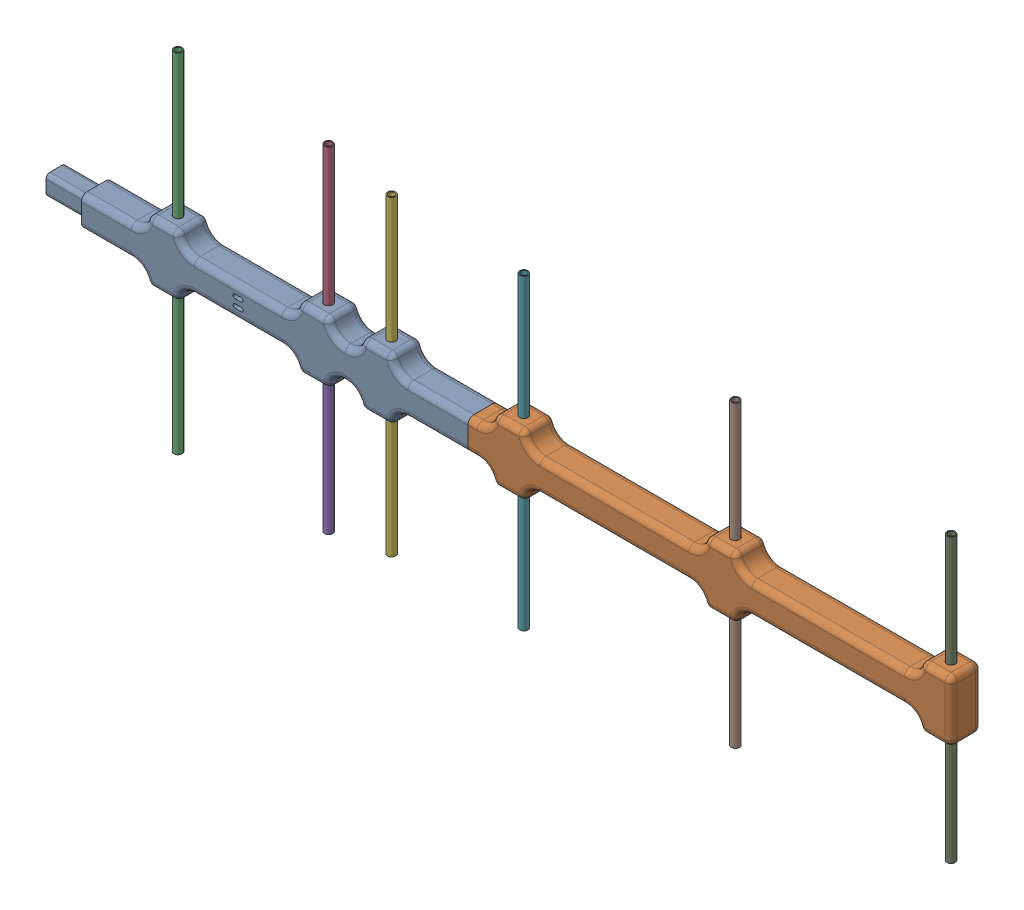
SolidWorks assembly LoRa 6 Elements 868 MHz Yagi Antenna, configuration Default. Lengths in mm.
Overall size (447.5 171 15).
9 component instances, 8 part files, 17 mates.
Components (placement in the parent):
- LoRa 6 Elements 868 MHz Yagi Antenna Back Side-1: LoRa 6 Elements 868 MHz Yagi Antenna Back Side [Default] at origin size (210 30 15)
- LoRa 6 Elements 868 MHz Yagi Antenna Front Side-1: LoRa 6 Elements 868 MHz Yagi Antenna Front Side [Default] at origin size (265.5 30 15)
- Reflector 171 mm-1: Reflector 171 mm [Default] at (-190 0 0) size (4 171 4)
- Driven Element 80mm-1: Driven Element 80mm [Default] at (-116 42.5 0) x (0.215404 0 0.976525) z (-0.976525 0 0.215404) size (4 80 4)
- Driven Element 80mm-2: Driven Element 80mm [Default] at (-116 -42.5 0) x (0.995024 0 -0.099633) z (0.099633 0 0.995024) size (4 80 4)
- Element 153mm-1: Element 153mm [Default] at (-85 0 0) x (0.953503 0 -0.301384) z (0.301384 0 0.953503) size (4 153 4)
- Element 151mm-1: Element 151mm [Default] at (-20 0 0) x (0.200414 0 -0.979711) z (0.979711 0 0.200414) size (4 151 4)
- Element 147mm-1: Element 147mm [Default] at (84 0 0) x (0.686761 0 -0.726884) z (0.726884 0 0.686761) size (4 147 4)
- Element 139mm-1: Element 139mm [Default] at (190 0 0) size (4 139 4)
Mates (geometry in assembly coordinates):
- Coincident4: coincident aligned: plane of LoRa 6 Elements 868 MHz Yagi Antenna Back Side-1 through (-200 7.5 -7.5) normal (0 0 -1); plane of DE1CTL 868 MHz Yagi Antenna Front Side-1 through (-200 7.5 -7.5) normal (0 0 -1)
- Coincident5: coincident aligned: plane of LoRa 6 Elements 868 MHz Yagi Antenna Back Side-1 through (0 -7.5 0) normal (0 -1 0); plane of DE1CTL 868 MHz Yagi Antenna Front Side-1 through (0 -7.5 0) normal (0 -1 0)
- Concentric1: concentric aligned: cylinder of LoRa 6 Elements 868 MHz Yagi Antenna Back Side-1 through (-190 -7.5 0) axis (0 -1 0) radius 2.05; cylinder of Reflector 171 mm-1 through (-190 85.5 0) axis (0 -1 0) radius 2
- Width1: width aligned: plane of Reflector 171 mm-1 through (-190 85.5 0) normal (0 1 0); plane of Reflector 171 mm-1 through (-190 -85.5 0) normal (0 -1 0); plane of LoRa 6 Elements 868 MHz Yagi Antenna Back Side-1 through (0 15 0) normal (0 1 0); plane of LoRa 6 Elements 868 MHz Yagi Antenna Back Side-1 through (0 -15 0) normal (0 -1 0)
- Concentric2: concentric aligned: cylinder of LoRa 6 Elements 868 MHz Yagi Antenna Back Side-1 through (-116 -7.5 0) axis (0 -1 0) radius 2.05; cylinder of Driven Element 80mm-1 through (-116 82.5 0) axis (0 -1 0) radius 2
- Coincident7: coincident anti-aligned: plane of LoRa 6 Elements 868 MHz Yagi Antenna Back Side-1 through (-116 2.5 0) normal (0 1 0); plane of Driven Element 80mm-1 through (-116 2.5 0) normal (0 -1 0)
- Concentric3: concentric aligned: cylinder of LoRa 6 Elements 868 MHz Yagi Antenna Back Side-1 through (-116 -7.5 0) axis (0 -1 0) radius 2.05; cylinder of Driven Element 80mm-2 through (-116 -2.5 0) axis (0 -1 0) radius 2
- Coincident8: coincident anti-aligned: plane of LoRa 6 Elements 868 MHz Yagi Antenna Back Side-1 through (-116 -2.5 0) normal (0 -1 0); plane of Driven Element 80mm-2 through (-116 -2.5 0) normal (0 1 0)
- Concentric4: concentric aligned: cylinder of LoRa 6 Elements 868 MHz Yagi Antenna Back Side-1 through (-85 -7.5 0) axis (0 -1 0) radius 2.05; cylinder of Element 153mm-1 through (-85 76.5 0) axis (0 -1 0) radius 2
- Width2: width anti-aligned: plane of Element 153mm-1 through (-85 76.5 0) normal (0 1 0); plane of Element 153mm-1 through (-85 -76.5 0) normal (0 -1 0); plane of LoRa 6 Elements 868 MHz Yagi Antenna Back Side-1 through (0 -15 0) normal (0 -1 0); plane of LoRa 6 Elements 868 MHz Yagi Antenna Back Side-1 through (0 15 0) normal (0 1 0)
- Concentric5: concentric aligned: cylinder of DE1CTL 868 MHz Yagi Antenna Front Side-1 through (-20 -7.5 0) axis (0 -1 0) radius 2.05; cylinder of Element 151mm-1 through (-20 75.5 0) axis (0 -1 0) radius 2
- Width3: width anti-aligned: plane of Element 151mm-1 through (-20 -75.5 0) normal (0 -1 0); plane of Element 151mm-1 through (-20 75.5 0) normal (0 1 0); plane of DE1CTL 868 MHz Yagi Antenna Front Side-1 through (0 15 0) normal (0 1 0); plane of DE1CTL 868 MHz Yagi Antenna Front Side-1 through (0 -15 0) normal (0 -1 0)
- Concentric6: concentric aligned: cylinder of DE1CTL 868 MHz Yagi Antenna Front Side-1 through (84 -7.5 0) axis (0 -1 0) radius 2.05; cylinder of Element 147mm-1 through (84 73.5 0) axis (0 -1 0) radius 2
- Width4: width anti-aligned: plane of Element 147mm-1 through (84 -73.5 0) normal (0 -1 0); plane of Element 147mm-1 through (84 73.5 0) normal (0 1 0); plane of DE1CTL 868 MHz Yagi Antenna Front Side-1 through (0 15 0) normal (0 1 0); plane of DE1CTL 868 MHz Yagi Antenna Front Side-1 through (0 -15 0) normal (0 -1 0)
- Concentric7: concentric aligned: cylinder of DE1CTL 868 MHz Yagi Antenna Front Side-1 through (190 -7.5 0) axis (0 -1 0) radius 2.05; cylinder of Element 139mm-1 through (190 69.5 0) axis (0 -1 0) radius 2
- Width5: width anti-aligned: plane of Element 139mm-1 through (190 -69.5 0) normal (0 -1 0); plane of Element 139mm-1 through (190 69.5 0) normal (0 1 0); plane of DE1CTL 868 MHz Yagi Antenna Front Side-1 through (0 15 0) normal (0 1 0); plane of DE1CTL 868 MHz Yagi Antenna Front Side-1 through (0 -15 0) normal (0 -1 0)
- Coincident9: coincident anti-aligned: plane of LoRa 6 Elements 868 MHz Yagi Antenna Back Side-1 through (-40 7.5 -7.51) normal (1 0 0); plane of DE1CTL 868 MHz Yagi Antenna Front Side-1 through (-40 7.5 -7.51) normal (-1 0 0)
